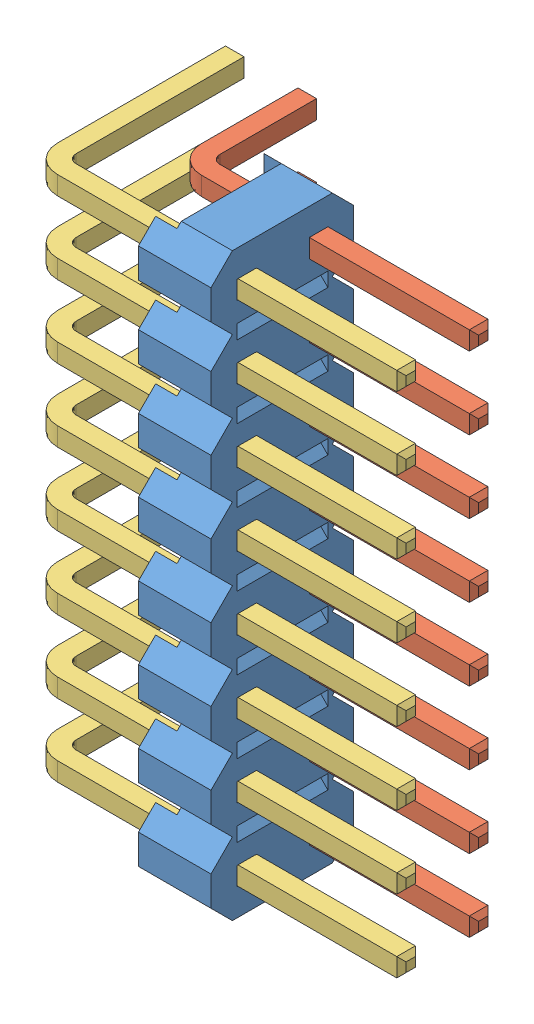
SolidWorks assembly PLD-16R, configuration Default. Lengths in mm.
Overall size (13.04 20.32 7.95).
17 component instances, 3 part files, 0 mates.
Components (placement in the parent):
- PLD-16 plastic-1: PLD-16 plastic [Default] at (2.2 -0.32 5.45) x (0 -1 0) z (1 0 0) size (20.32 5 2.54)
- PLD-R-PIN-1: PLD-R-PIN [Default] x (1 0 0) z (0 -1 0) size (10.5 4.5 0.65)
- PLD-R-PIN-2: PLD-R-PIN [Default] at (0 -2.54 0) x (1 0 0) z (0 -1 0) size (10.5 4.5 0.65)
- PLD-R-PIN-3: PLD-R-PIN [Default] at (0 -5.08 0) x (1 0 0) z (0 -1 0) size (10.5 4.5 0.65)
- PLD-R-PIN-4: PLD-R-PIN [Default] at (0 -7.62 0) x (1 0 0) z (0 -1 0) size (10.5 4.5 0.65)
- PLD-R-PIN-5: PLD-R-PIN [Default] at (0 -10.16 0) x (1 0 0) z (0 -1 0) size (10.5 4.5 0.65)
- PLD-R-PIN-6: PLD-R-PIN [Default] at (0 -12.7 0) x (1 0 0) z (0 -1 0) size (10.5 4.5 0.65)
- PLD-R-PIN-7: PLD-R-PIN [Default] at (0 -15.24 0) x (1 0 0) z (0 -1 0) size (10.5 4.5 0.65)
- PLD-R-PIN-8: PLD-R-PIN [Default] at (0 -17.78 0) x (1 0 0) z (0 -1 0) size (10.5 4.5 0.65)
- PLD_R_PIN_BIG-1: PLD_R_PIN_BIG [Default] at (-2.54 0 0) x (1 0 0) z (0 -1 0) size (13 7 0.65)
- PLD_R_PIN_BIG-2: PLD_R_PIN_BIG [Default] at (-2.54 -2.54 0) x (1 0 0) z (0 -1 0) size (13 7 0.65)
- PLD_R_PIN_BIG-3: PLD_R_PIN_BIG [Default] at (-2.54 -5.08 0) x (1 0 0) z (0 -1 0) size (13 7 0.65)
- PLD_R_PIN_BIG-4: PLD_R_PIN_BIG [Default] at (-2.54 -7.62 0) x (1 0 0) z (0 -1 0) size (13 7 0.65)
- PLD_R_PIN_BIG-5: PLD_R_PIN_BIG [Default] at (-2.54 -10.16 0) x (1 0 0) z (0 -1 0) size (13 7 0.65)
- PLD_R_PIN_BIG-6: PLD_R_PIN_BIG [Default] at (-2.54 -12.7 0) x (1 0 0) z (0 -1 0) size (13 7 0.65)
- PLD_R_PIN_BIG-7: PLD_R_PIN_BIG [Default] at (-2.54 -15.24 0) x (1 0 0) z (0 -1 0) size (13 7 0.65)
- PLD_R_PIN_BIG-8: PLD_R_PIN_BIG [Default] at (-2.54 -17.78 0) x (1 0 0) z (0 -1 0) size (13 7 0.65)
